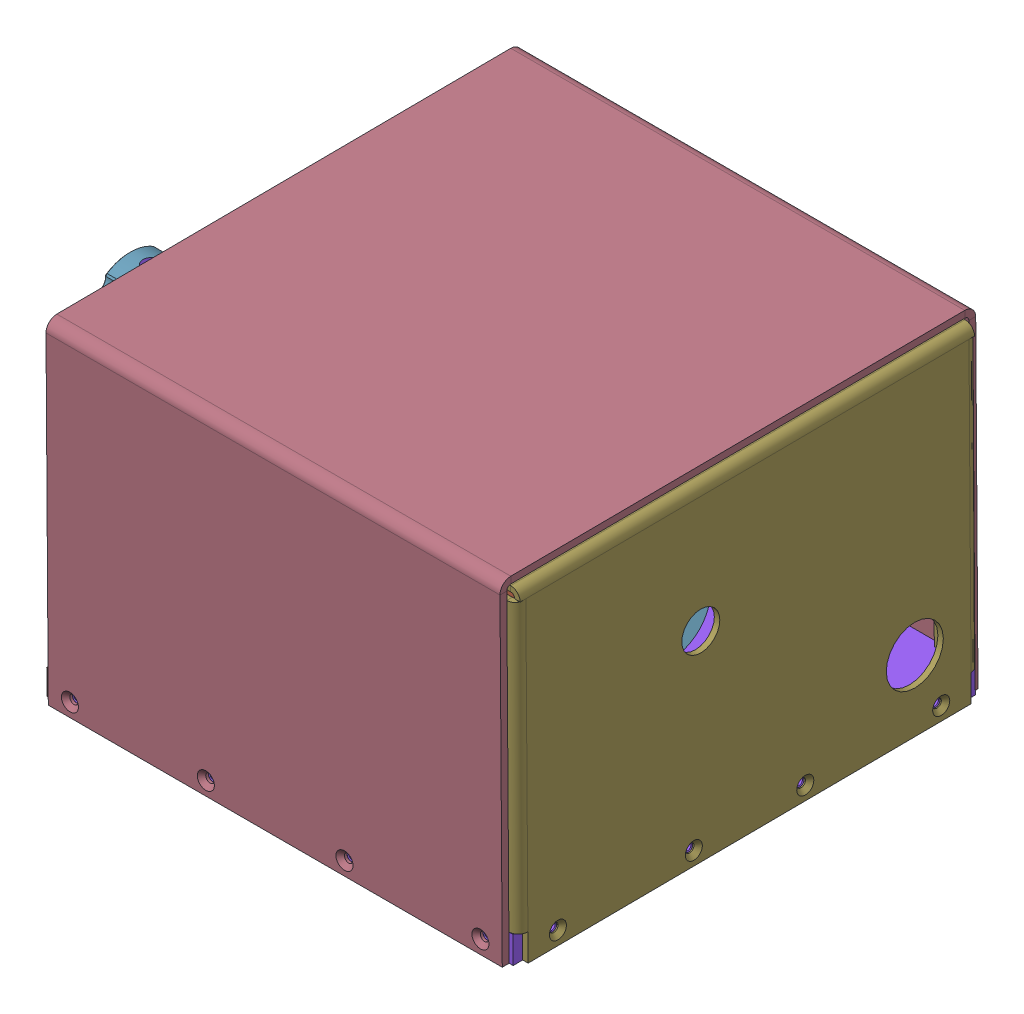
SolidWorks assembly Interferometer assembly new coupler, configuration Default. Lengths in mm.
Overall size (210.08 124.23 175.86).
21 component instances, 17 part files, 34 mates.
Components (placement in the parent):
- step_68636.step-1: step_68636.step [Default] at (40.039 -44.6671 -9.5355) x (0.999987 -0.000036 0.005042) z (-0.005042 -0.007058 0.999962) size (68.43 21 147.5)
- iges_68454.igs-1: iges_68454.igs [Default] at (85.7356 92.6203 -24.8825) x (0 0 1) z (-1 0 0) size (35.62 33.53 128.33)
- U200-A3K-1: U200-A3K [U200-A] at (22.4859 47.0596 -56.1191) x (0 0.007058 -0.999975) z (1 0 0) size (76.15 75.89 53.49)
- Newport-U200-A3K interface-1: Newport-U200-A3K interface [Default] at (30.4234 13.8163 -65.2897) x (0.005042 0.007058 -0.999962) z (0.999987 -0.000036 0.005042) size (45 7.6 15)
- kineflex coupler-1: kineflex coupler [Default] at (80.9067 56.435 -66.4155) x (0 -0.007058 0.999975) z (0 0.999975 0.007058) size (31.7 64 31.7)
- glass cube assembly-1: glass cube assembly [Default] at (38.5504 56.3403 -64.9895) x (0 -0.007058 0.999975) z (-1 0 0) size (50.8 52.69 33)
  - glass cube holder-1: glass cube holder [Default] at (0 0 5.7888) x (0 -1 0) z (0 0 1) size (52.69 50.8 33)
  - interferometer glass cube-1: interferometer glass cube [Default] at (-10 0 6.2888) x (1 0 0) z (0 -1 0) size (20 32.5 20)
- new base-1: new base [Default] at (90.0973 -16.9568 -97.5406) x (1 0 0) z (0 -0.007058 0.999975) size (170 10 170)
- coupler mount 1-1: coupler mount 1 [Default] at (-11.8954 -7.1349 -72.2674) x (1 0 0) z (0 -0.007058 0.999975) size (20 83 34.7)
- coupler mount 2-1: coupler mount 2 [Default] at (76.5636 72.8536 -70.3528) x (-1 0 0) z (0 -0.007058 0.999975) size (40 80 31.7)
- box front-1: box front [Default] at (-17.7385 47.2669 -91.2872) x (0 -0.007058 0.999975) z (-1 0 0) size (170 120.49 14)
- box back-1: box back [Default] at (155.7615 68.8503 -86.0064) x (0 -0.007058 0.999975) z (-1 0 0) size (170 120 15)
- lid-1: lid [Default] at (121.528 103.1746 -46.3119) x (0 0.007058 -0.999975) z (-1 0 0) size (175 123 167)
- New laser incoupler-1: New laser incoupler [Default] at (-19.3911 65.5378 -27.9979) x (0 -0.999975 -0.007058) z (0 0.007058 -0.999975) size (31.7 41 31.7)
  - in coupler-1: in coupler [Default] at (9.3737 -6.068 38.3523) size (31.7 41 31.7)
  - in coupler insert-1: in coupler insert [Default] at (9.3737 -3.068 38.3523) size (21 38 21)
  - 3-16in steel ball-1: 3-16in steel ball [Default] at (1.8375 3.932 38.3523) x (0.568361 0.821082 -0.052813) z (-0.819572 0.559316 -0.124369) size (4.76 4.76 4.76)
  - 3-16in steel ball-2: 3-16in steel ball [Default] at (1.8375 26.932 38.3523) x (-0.957727 -0.083912 0.275168) z (0.285332 -0.15517 0.945784) size (4.76 4.76 4.76)
  - M6x1.0x4 set screw mock up-1: M6x1.0x4 set screw mock up [Default] at (-2.4763 26.932 38.3523) x (0 0.935585 -0.353101) z (0 0.353101 0.935585) size (6 4 6)
  - M6x1.0x4 set screw mock up-2: M6x1.0x4 set screw mock up [Default] at (-6.4763 3.932 38.3523) x (0 0.572959 -0.819584) z (0 -0.819584 -0.572959) size (6 4 6)
Mates (geometry in assembly coordinates):
- Concentric4: concentric aligned: cylinder of U200-A3K-1 through (30.4234 21.4162 -65.236) axis (0 -0.999975 -0.007058) radius 2.159; cylinder of Newport-U200-A3K interface-1 through (30.4234 21.4162 -65.236) axis (0 -0.999975 -0.007058) radius 2.15
- Coincident14: coincident anti-aligned: plane of U200-A3K-1 through (38.3609 21.2145 -36.6617) normal (0 -0.999975 -0.007058); plane of Newport-U200-A3K interface-1 through (30.4234 21.4162 -65.236) normal (0 0.999975 0.007058)
- Coincident15: coincident anti-aligned: plane of step_68636.step-1 through (50.1102 14.0775 -102.2899) normal (0 0.999975 0.007058); plane of Newport-U200-A3K interface-1 through (30.4234 13.8163 -65.2897) normal (0 -0.999975 -0.007058)
- Coincident41: coincident: line of kineflex coupler-1 through (156.2569 56.435 -66.4155) axis (-1 0 0)
- Distance4: distance = 12 mm aligned: plane of Newport-U200-A3K interface-1 through (37.8099 21.2571 -42.6991) normal (0.999987 -0.000036 0.005042); plane of step_68636.step-1 through (50.1102 14.0775 -102.2899) normal (0.999987 -0.000036 0.005042)
- Distance5: distance = 11.3 mm aligned: plane of step_68636.step-1 through (49.8667 10.0367 -54.0179) normal (-0.005042 -0.007058 0.999962); plane of Newport-U200-A3K interface-1 through (37.8099 21.2571 -42.6991) normal (-0.005042 -0.007058 0.999962)
- Coincident45: coincident anti-aligned: plane of step_68636.step-1 through (27.7334 -7.4491 -27.7519) normal (0 -0.999975 -0.007058); plane of new base-1 through (90.0973 -6.957 -97.47) normal (0 0.999975 0.007058)
- Coincident48: coincident anti-aligned: plane of new base-1 through (90.0973 -6.957 -97.47) normal (0 0.999975 0.007058); plane of coupler mount 1-1 through (-11.8954 -7.1349 -72.2674) normal (0 -0.999975 -0.007058)
- Coincident52: coincident anti-aligned: plane of new base-1 through (90.0973 -6.957 -97.47) normal (0 0.999975 0.007058); plane of coupler mount 2-1 through (76.5636 -7.1445 -70.9174) normal (0 -0.999975 -0.007058)
- Coincident56: coincident anti-aligned: plane of kineflex coupler-1 through (80.9067 56.435 -66.4155) normal (-1 0 0); plane of coupler mount 2-1 through (80.9067 -7.0612 -82.714) normal (1 0 0)
- Parallel10: parallel aligned: plane of kineflex coupler-1 through (83.9067 72.3965 -82.1532) normal (0 0.999975 0.007058); plane of coupler mount 2-1 through (76.5636 72.8536 -70.3528) normal (0 0.999975 0.007058)
- Parallel11: parallel aligned: plane of new base-1 through (153.7615 -6.4499 -169.3201) normal (1 0 0); plane of coupler mount 2-1 through (80.9067 -7.0612 -82.714) normal (1 0 0)
- Parallel12: parallel anti-aligned: plane of new base-1 through (-16.2385 -6.4499 -169.3201) normal (-1 0 0)
- Coincident58: coincident aligned: plane of kineflex coupler-1 through (83.9067 72.1727 -50.454) normal (0 -0.007058 0.999975); plane of coupler mount 2-1 through (80.9067 -7.2849 -51.0148) normal (0 -0.007058 0.999975)
- Coincident61: coincident aligned: plane of new base-1 through (-16.2385 -6.4499 -169.3201) normal (-1 0 0); plane of coupler mount 1-1 through (-16.2385 75.9463 -83.4782) normal (-1 0 0)
- Coincident63: coincident anti-aligned: plane of new base-1 through (90.0973 -6.957 -97.47) normal (0 0.999975 0.007058); plane of coupler mount 2-1 through (76.5636 -7.1445 -70.9174) normal (0 -0.999975 -0.007058)
- Coincident64: coincident anti-aligned: plane of new base-1 through (-16.2385 -6.4499 -169.3201) normal (-1 0 0); plane of box front-1 through (-16.2385 47.2669 -91.2872) normal (1 0 0)
- Coincident65: coincident aligned: plane of new base-1 through (90.0973 -16.9568 -97.5406) normal (0 -0.999975 -0.007058); plane of box front-1 through (-16.2385 -16.4497 -169.3907) normal (0 -0.999975 -0.007058)
- Coincident70: coincident anti-aligned: plane of new base-1 through (153.7615 -6.4499 -169.3201) normal (1 0 0); plane of box back-1 through (153.7615 68.8503 -86.0064) normal (-1 0 0)
- Coincident71: coincident aligned: plane of new base-1 through (90.0973 -16.9568 -97.5406) normal (0 -0.999975 -0.007058); plane of box back-1 through (153.7615 -16.4497 -169.3907) normal (0 -0.999975 -0.007058)
- Coincident72: coincident aligned: plane of new base-1 through (-16.2385 -6.4499 -169.3201) normal (0 0.007058 -0.999975); plane of box back-1 through (155.7615 69.4346 -168.7845) normal (0 0.007058 -0.999975)
- Coincident74: coincident anti-aligned: plane of box front-1 through (-17.7385 103.4893 -90.8904) normal (0 0.999975 0.007058); plane of lid-1 through (121.528 103.1746 -46.3119) normal (0 -0.999975 -0.007058)
- Coincident75: coincident: line of box back-1 through (152.2615 103.5372 -167.1102) axis (0 -0.007058 0.999975); plane of lid-1 through (152.2615 105.3374 1.4731) normal (1 0 0)
- Coincident76: coincident anti-aligned: plane of U200-A3K-1 through (17.7615 40.9682 -77.887) normal (-1 0 0); plane of glass cube assembly-1/glass cube holder-1 through (17.7615 56.3403 -64.9895) normal (1 0 0)
- Concentric18: concentric anti-aligned: cylinder of U200-A3K-1 through (19.2855 56.3403 -64.9895) axis (-1 0 0) radius 23.876; cylinder of glass cube assembly-1/glass cube holder-1 through (17.7615 56.3403 -64.9895) axis (1 0 0) radius 23
- Concentric19: concentric aligned: cylinder of new base-1 through (-6.2385 -17.1739 -66.785) axis (0 -0.999975 -0.007058) radius 5.5; cylinder of coupler mount 1-1 through (-6.2385 -7.1741 -66.7144) axis (0 -0.999975 -0.007058) radius 2.5
- Concentric20: concentric aligned: circle of new base-1; circle of coupler mount 2-1
- Concentric21: concentric aligned: circle of new base-1; circle of coupler mount 2-1
- Concentric23: concentric anti-aligned: circle of step_68636.step-1; circle of new base-1
- Parallel13: parallel aligned: plane of glass cube assembly-1/glass cube holder-1 through (32.7615 45.7406 -65.0643) normal (0 -0.007058 0.999975); plane of coupler mount 1-1 through (-16.2385 75.7014 -48.779) normal (0 -0.007058 0.999975)
- Concentric25: concentric aligned: circle of coupler mount 1-1; circle of New laser incoupler-1/in coupler-1
- Concentric26: concentric aligned: cone of coupler mount 1-1 through (-8.7385 44.0235 -79.0034) axis (1 0 0); circle of New laser incoupler-1/in coupler-1
- Coincident80: coincident aligned: line of kineflex coupler-1 through (156.2569 56.435 -66.4155) axis (-1 0 0); line of New laser incoupler-1 through (-9.4156 56.435 -66.4155) axis (-1 0 0)
- Concentric27: concentric anti-aligned: circle of coupler mount 1-1; circle of New laser incoupler-1/in coupler insert-1
